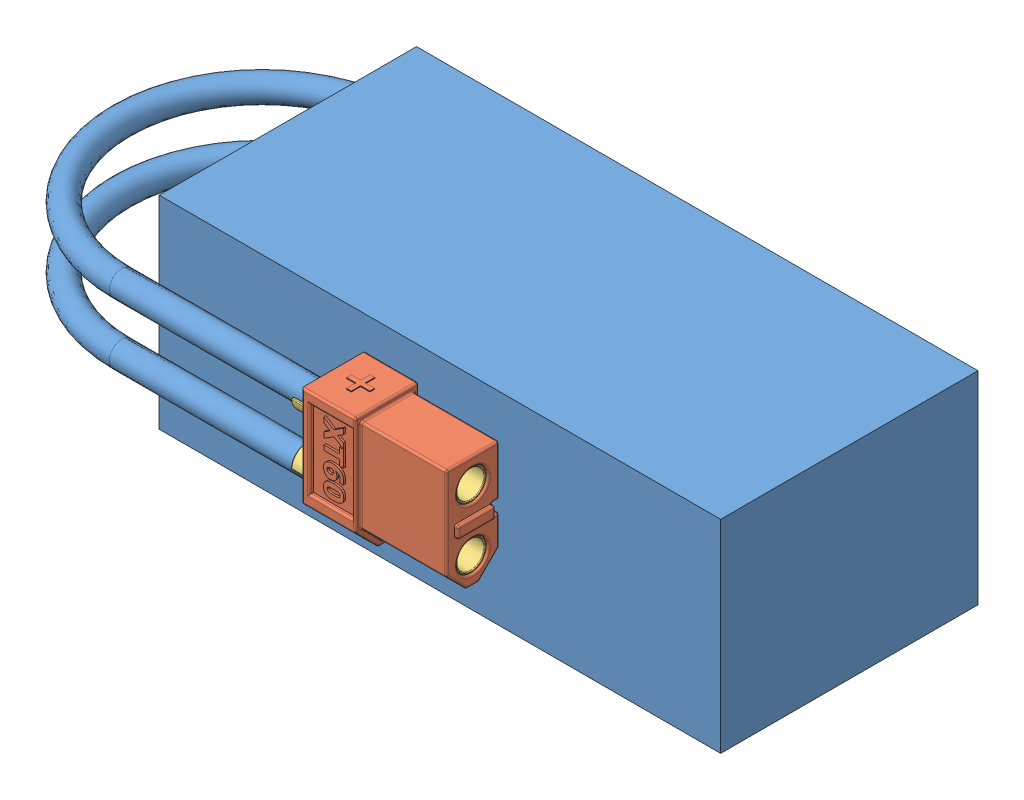
SolidWorks assembly Batterie, configuration Défaut. Lengths in mm.
Overall size (91.6 26 41.86).
5 component instances, 3 part files, 0 mates.
Components (placement in the parent):
- corps batterie-1: corps batterie [Défaut] at origin size (91.6 26 39.4)
- XT60 Connector Female Connector-1: XT60 Connector Female Connector [Défaut] at (26.8962 22.6083 25.3642) x (0 0 -1) z (-1 0 0) size (8.13 15.93 21.83)
  - XT60 Connector Female Housing-1: XT60 Connector Female Housing [Défaut] at origin size (8.13 15.93 18.38)
  - XT60 Connector Female Contact-1: XT60 Connector Female Contact [Défaut] at (4.064 3.934 39.207) x (1 0 0) z (0 0 -1) size (4 4 21.09)
  - XT60 Connector Female Contact-2: XT60 Connector Female Contact [Défaut] at (4.064 11.801 39.207) x (-1 0 0) z (0 0 -1) size (4 4 21.09)
